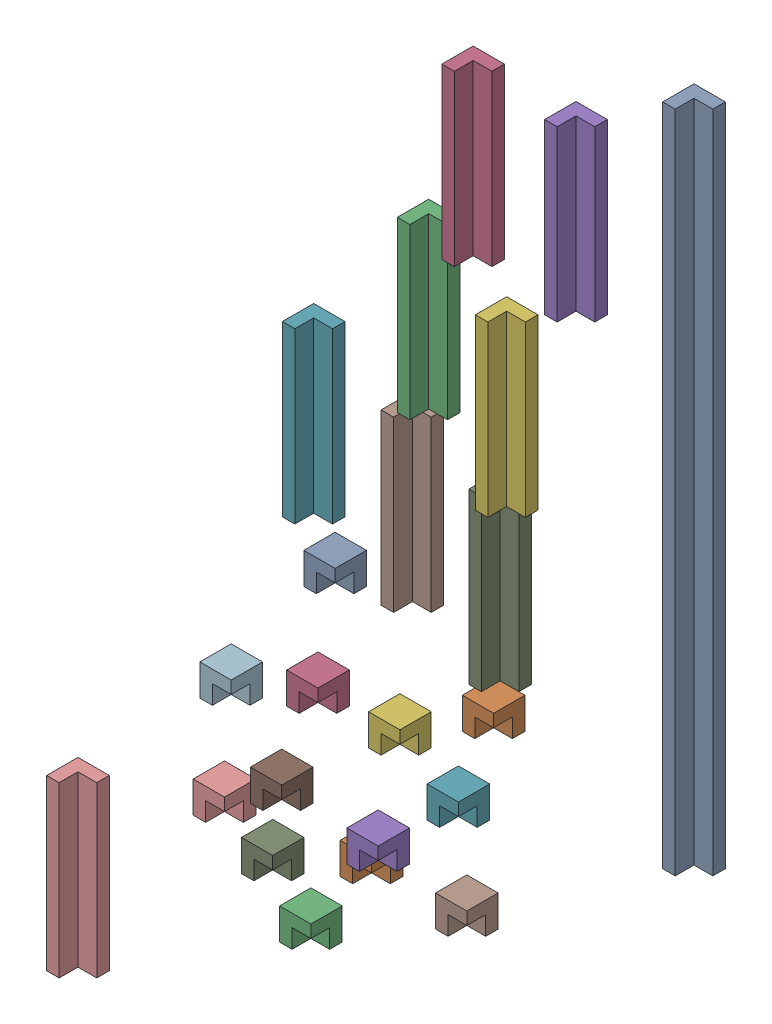
SolidWorks assembly LayerAssembly, configuration Default. Lengths in mm.
Overall size (63.74 140.08 44.6).
22 component instances, 3 part files, 0 mates.
Components (placement in the parent):
- Beam106-1: Beam106 [Default] at (9.4821 -22.398 50.0399) size (5 106 5)
- Corner3-1: Corner3 [Default] at (-9.9293 -6.4709 63.7787) size (5 5 5)
- Beam27-1: Beam27 [Default] at (-5.9629 41.5452 72.9046) size (5 27 5)
- Corner3-2: Corner3 [Default] at (-25.51 -4.5459 76.2325) size (5 5 5)
- Corner3-3: Corner3 [Default] at (-20.4363 -26.114 71.6983) size (5 5 5)
- Corner3-4: Corner3 [Default] at (-19.0997 -10.4476 69.5647) size (5 5 5)
- Corner3-5: Corner3 [Default] at (-13.3737 -19.377 65.952) size (5 5 5)
- Corner3-6: Corner3 [Default] at (-14.0011 -35.7404 63.9767) size (5 5 5)
- Corner3-7: Corner3 [Default] at (-30.2355 -28.8064 78.7298) size (5 5 5)
- Corner3-8: Corner3 [Default] at (-32.7637 -19.411 83.8976) size (5 5 5)
- Corner3-9: Corner3 [Default] at (-27.7297 -17.2962 79.7988) size (5 5 5)
- Corner3-10: Corner3 [Default] at (-33.439 -4.435 82.1578) size (5 5 5)
- Corner3-11: Corner3 [Default] at (-25.4383 10.6969 73.564) size (5 5 5)
- Corner3-12: Corner3 [Default] at (-24.1536 -31.0124 69.0446) size (5 5 5)
- Corner3-13: Corner3 [Default] at (-33.2385 -44.3231 69.6343) size (5 5 5)
- Beam27-2: Beam27 [Default] at (1.8654 66.9992 73.6368) size (5 27 5)
- Beam27-3: Beam27 [Default] at (3.3341 52.6002 58.6918) size (5 27 5)
- Beam27-4: Beam27 [Default] at (-3.4495 24.3538 62.9719) size (5 27 5)
- Beam27-5: Beam27 [Default] at (-22.3387 19.9372 74.8899) size (5 27 5)
- Beam27-6: Beam27 [Default] at (-12.6739 9.5037 68.792) size (5 27 5)
- Beam27-7: Beam27 [Default] at (-4.6535 -0.4269 62.8089) size (5 27 5)
- Beam27-8: Beam27 [Default] at (-44.417 -46.0781 90.4321) size (5 27 5)
